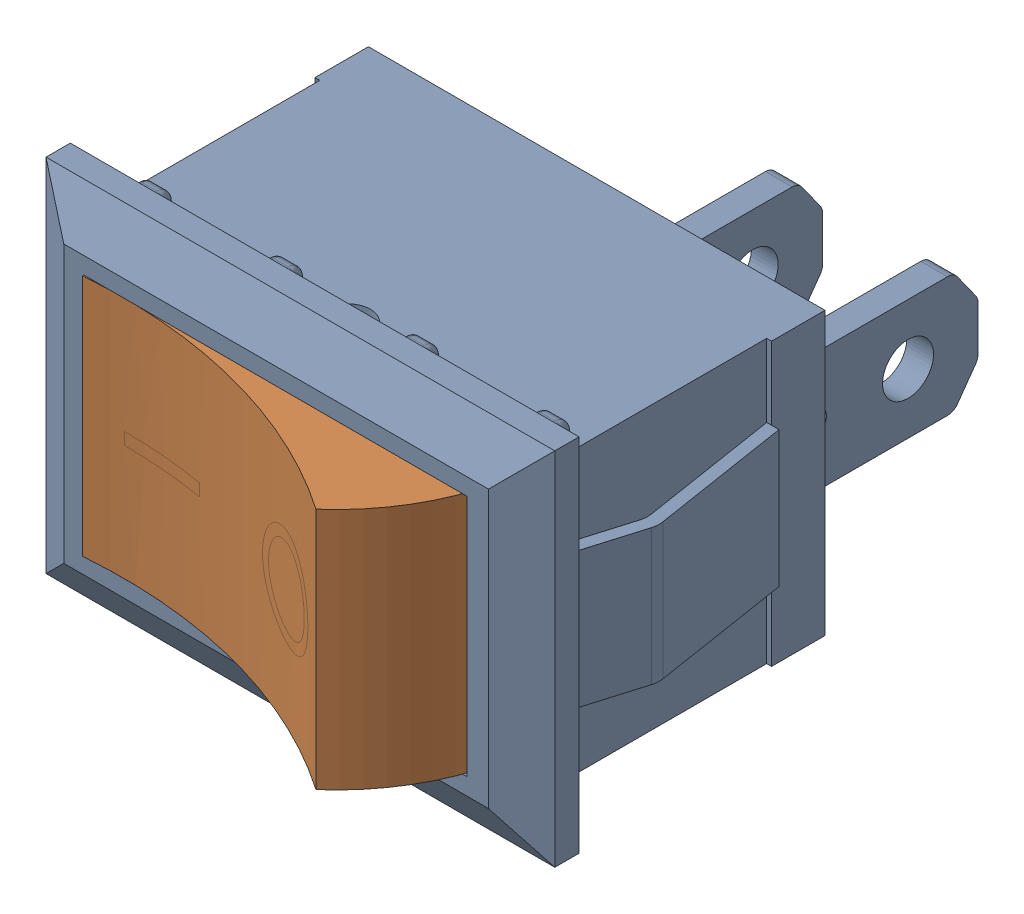
SolidWorks assembly Switch Montaj, configuration Varsayılan. Lengths in mm.
Overall size (21.23 14.85 25.41).
2 component instances, 2 part files, 3 mates.
Components (placement in the parent):
- Switch-1: Switch [Varsayılan] at (-10.7432 -5.856 23) size (21.23 14.85 21.45)
- Switch Açma Kapama-2: Switch Açma Kapama [Varsayılan] at (-0.3897 4.944 31.6284) x (0.965926 0 0.258819) z (0 -1 0) size (16.31 8 10)
Mates (geometry in assembly coordinates):
- Eş Merkezli1: concentric anti-aligned: cylinder of Switch-1 through (-1.3432 -14.256 33.2472) axis (0 1 0) radius 0.925; circle of Switch Açma Kapama-2
- Çakışık15: coincident anti-aligned: plane of Switch-1 through (-9.1911 4.944 30.2) normal (0 -1 0); plane of Switch Açma Kapama-2 through (-1.9547 4.944 33.1081) normal (0 1 0)
- Açıyı Sınırla2: limit planar angle = 2.879793 rad aligned: plane of Switch Açma Kapama-2 through (-7.6739 -5.056 28.3962) normal (0.258819 0 -0.965926); plane of Switch-1 through (-10.7432 -5.856 30.2) normal (0 0 1)
